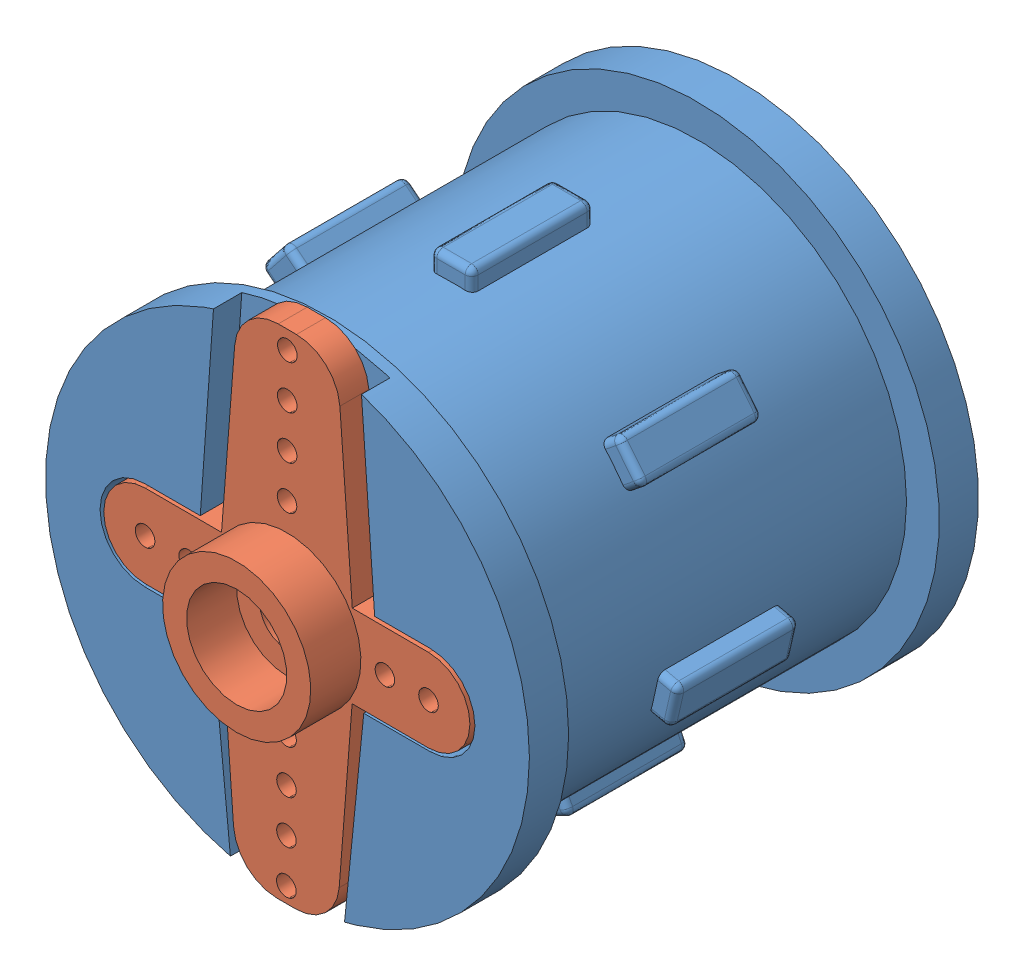
SolidWorks assembly Baugruppe_Antriebsrad, configuration Standard. Lengths in mm.
Overall size (22.2 22.88 22.93).
3 component instances, 3 part files, 3 mates.
Components (placement in the parent):
- Antriebsrad-1: Antriebsrad [Standard] at origin size (22.2 22.2 20.6)
- Teil1^Baugruppe_Antriebsrad-1: Teil1^Baugruppe_Antriebsrad [Standard] at origin (virtual)
- Servohorn-1: Servohorn [Standard] at (0 0 9) x (-0.002161 -0.999998 0) z (0 0 1) size (22.84 16.8 3.63)
Mates (geometry in assembly coordinates):
- Deckungsgleich1: coincident anti-aligned: plane of Antriebsrad-1 through (0 0 9) normal (0 0 1); plane of Servohorn-1 through (0.036 16.65 9) normal (0 0 -1)
- Parallel1: parallel anti-aligned: cylinder of Antriebsrad-1 through (6.55 0 9) axis (0 0 1) radius 2.05; cylinder of Servohorn-1 through (6.5 -0.014 10.33) axis (0 0 -1) radius 1.9
- Konzentrisch3: concentric aligned: circle of Antriebsrad-1; circle of Servohorn-1
